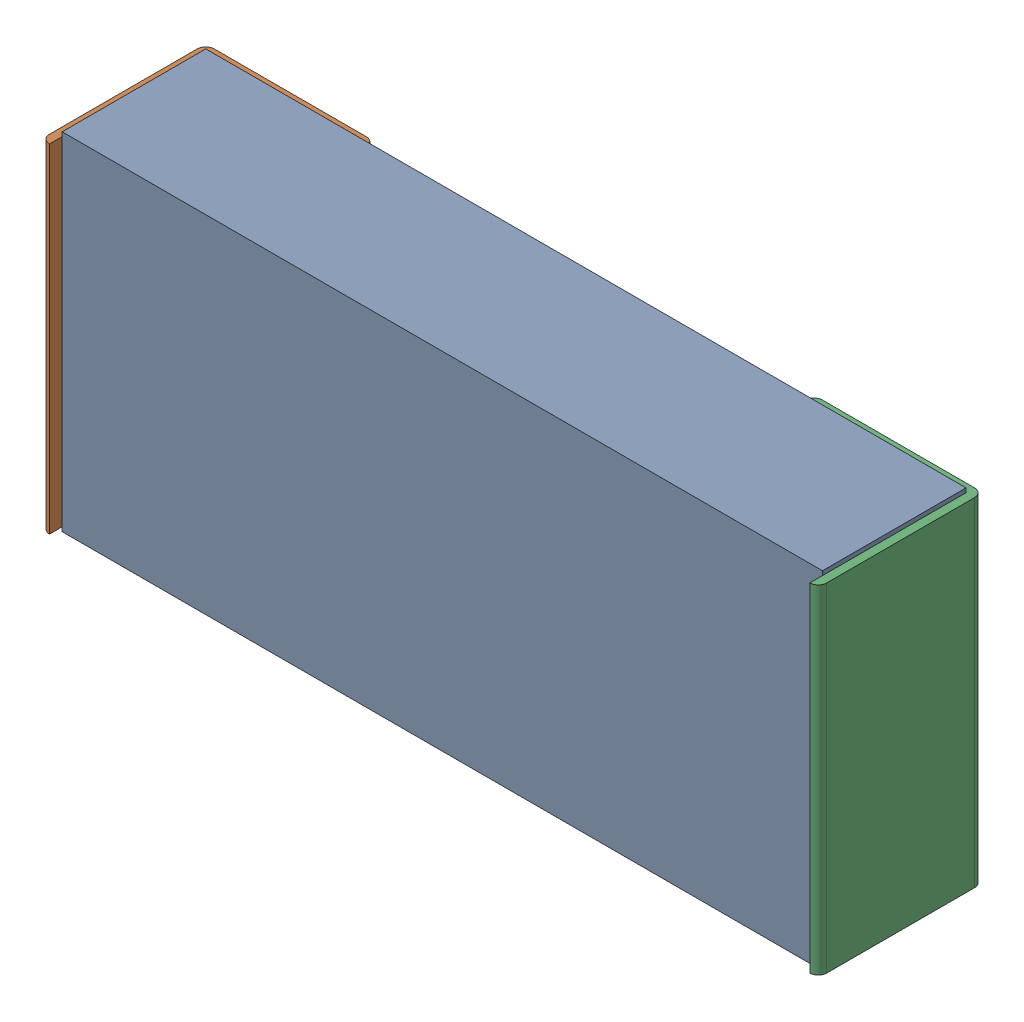
SolidWorks assembly C1, configuration Predeterminado. Lengths in mm.
Overall size (2.34 1.04 0.5).
4 component instances, 3 part files, 0 mates.
Components (placement in the parent):
- Open CASCADE STEP translator 6.8 1.5.1-1: Open CASCADE STEP translator 6.8 1.5.1 [Predeterminado] at origin size (2.34 1.04 0.5)
  - Body_1_2-1: Body_1_2 [Predeterminado] at origin size (2.29 1.04 0.43)
  - Pin_1_2-1: Pin_1_2 [Predeterminado] at (0.3048 0 0) x (-1 0 0) z (0 0 1) size (0.51 1.02 0.5)
  - Pin_2_2-1: Pin_2_2 [Predeterminado] at origin size (0.51 1.02 0.5)
